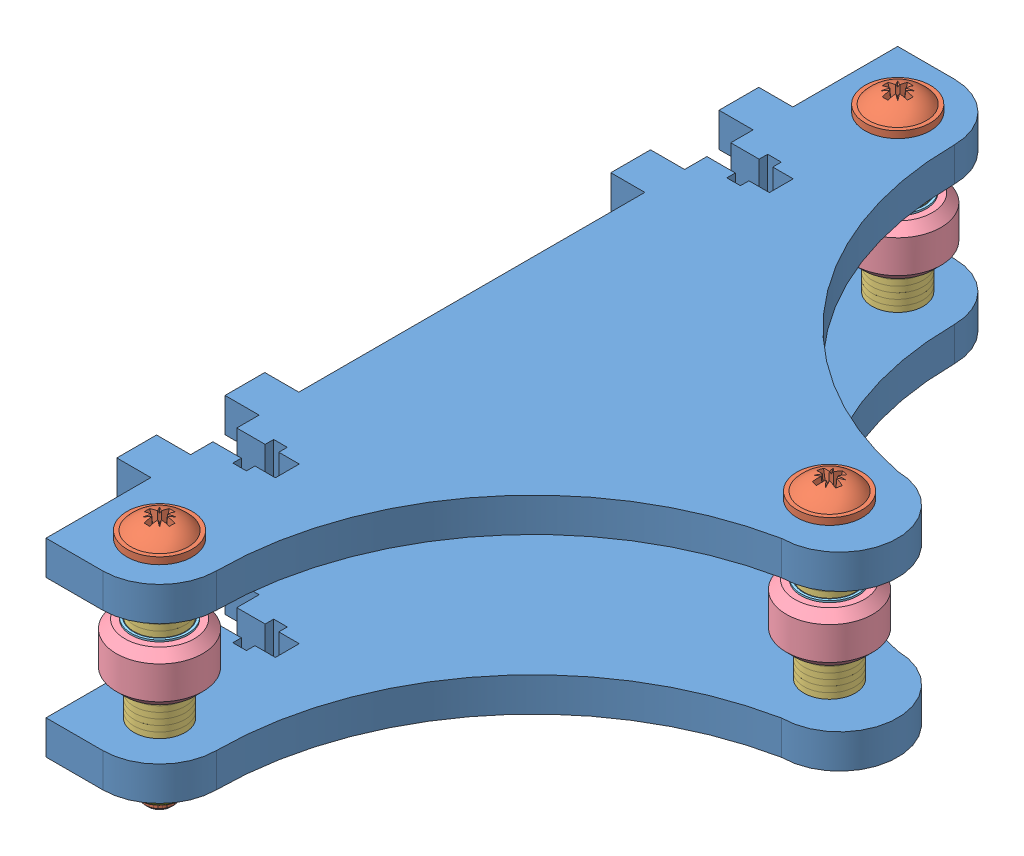
SolidWorks assembly carriage_axis_z, configuration По умолчанию. Lengths in mm.
Overall size (90 43.47 164.42).
59 component instances, 7 part files, 93 mates.
Components (placement in the parent):
- carriage_axis_z_plywood-3: carriage_axis_z_plywood [По умолчанию] at origin size (81.03 6 150)
- DIN967-1: DIN967 [М5х40] at (-25 9.55 -65) x (0 -1 0) z (0 0 1) size (43.47 34 34.42)
- DIN967-2: DIN967 [М5х40] at (-25 9.55 65) x (0 -1 0) z (0 0 1) size (43.47 34 34.42)
- DIN967-4: DIN967 [М5х40] at (28 9.55 0) x (0 -1 0) z (0.973575 0 0.228367) size (43.47 34 34.42)
- din433_m5-1: din433_m5 [По умолчанию] at (28 0 0) x (1 0 0) z (0 -1 0) size (9 9 1)
- din433_m5-2: din433_m5 [По умолчанию] at (28 -2 0) x (-0.882011 0 -0.471229) z (0 1 0) size (9 9 1)
- din433_m5-3: din433_m5 [По умолчанию] at (28 -3 0) x (-0.882011 0 -0.471229) z (0 1 0) size (9 9 1)
- din433_m5-4: din433_m5 [По умолчанию] at (28 -4 0) x (-0.882011 0 -0.471229) z (0 1 0) size (9 9 1)
- din433_m5-5: din433_m5 [По умолчанию] at (28 -5 0) x (-0.986157 0 -0.165812) z (0 1 0) size (9 9 1)
- din433_m5-12: din433_m5 [По умолчанию] at (-25 -3 65) x (-0.955012 0 -0.296566) z (0 1 0) size (9 9 1)
- din433_m5-13: din433_m5 [По умолчанию] at (-25 -4 65) x (-0.955012 0 -0.296566) z (0 1 0) size (9 9 1)
- din433_m5-14: din433_m5 [По умолчанию] at (-25 -5 65) x (-0.827257 0 -0.561823) z (0 1 0) size (9 9 1)
- din433_m5-15: din433_m5 [По умолчанию] at (-25 -2 65) x (-0.955012 0 -0.296566) z (0 1 0) size (9 9 1)
- din433_m5-16: din433_m5 [По умолчанию] at (-25 0 65) x (0.982082 0 -0.188455) z (0 -1 0) size (9 9 1)
- din433_m5-17: din433_m5 [По умолчанию] at (-25 -2 -65) x (-0.996489 0 -0.083718) z (0 1 0) size (9 9 1)
- din433_m5-18: din433_m5 [По умолчанию] at (-25 -3 -65) x (-0.996489 0 -0.083718) z (0 1 0) size (9 9 1)
- din433_m5-19: din433_m5 [По умолчанию] at (-25 -4 -65) x (-0.928921 0 -0.370279) z (0 1 0) size (9 9 1)
- din433_m5-20: din433_m5 [По умолчанию] at (-25 -1 -65) x (-0.996489 0 -0.083718) z (0 1 0) size (9 9 1)
- din433_m5-28: din433_m5 [По умолчанию] at (-25 -5 -65) x (0.980186 0 0.198081) z (0 -1 0) size (9 9 1)
- din433_m5-29: din433_m5 [По умолчанию] at (-25 -4 -65) x (0.980186 0 0.198081) z (0 -1 0) size (9 9 1)
- din433_m5-27: din433_m5 [По умолчанию] at (28 -5 0) x (0.91627 0 0.40056) z (0 -1 0) size (9 9 1)
- din433_m5-21: din433_m5 [По умолчанию] at (-25 -6 65) x (-0.552382 0 -0.833591) z (0 1 0) size (9 9 1)
- Delrin Mini V Wheel Kit-1: Delrin Mini V Wheel Kit [По умолчанию] at (-25 -10.7 65) x (0 1 0) z (0 0 1) size (9.4 15.23 15.23)
  - Delrin Mini V Wheel-1: Delrin Mini V Wheel [Default] at origin size (8.8 15.23 15.23)
  - Mini Ball Bearing 105zz 5x10x4-1: Mini Ball Bearing 105zz 5x10x4 [Default] at (2.6 0 0) size (4.2 10 10)
  - Mini Ball Bearing 105zz 5x10x4-2: Mini Ball Bearing 105zz 5x10x4 [Default] at (-2.6 0 0) size (4.2 10 10)
  - Mini V Wheel Precision Shim-2: Mini V Wheel Precision Shim [По умолчанию] at (-0.5 0 0) size (1 8 8)
- din433_m5-30: din433_m5 [По умолчанию] at (-25 -19.4 65) x (0.999952 0 0.009811) z (0 -1 0) size (9 9 1)
- din433_m5-31: din433_m5 [По умолчанию] at (-25 -20.4 65) x (0.999952 0 0.009811) z (0 -1 0) size (9 9 1)
- din433_m5-32: din433_m5 [По умолчанию] at (-25 -16.4 65) x (-0.994411 0 0.105575) z (0 1 0) size (9 9 1)
- din433_m5-33: din433_m5 [По умолчанию] at (-25 -19.4 65) x (-0.982057 0 -0.188585) z (0 1 0) size (9 9 1)
- din433_m5-34: din433_m5 [По умолчанию] at (-25 -18.4 65) x (-0.994411 0 0.105575) z (0 1 0) size (9 9 1)
- din433_m5-35: din433_m5 [По умолчанию] at (-25 -17.4 65) x (-0.994411 0 0.105575) z (0 1 0) size (9 9 1)
- Delrin Mini V Wheel Kit-2: Delrin Mini V Wheel Kit [По умолчанию] at (-25 -10.7 -65) x (0 -1 0) z (0.990454 0 -0.137844) size (9.4 15.23 15.23)
  - Delrin Mini V Wheel-1: Delrin Mini V Wheel [Default] at origin size (8.8 15.23 15.23)
  - Mini Ball Bearing 105zz 5x10x4-1: Mini Ball Bearing 105zz 5x10x4 [Default] at (2.6 0 0) size (4.2 10 10)
  - Mini Ball Bearing 105zz 5x10x4-2: Mini Ball Bearing 105zz 5x10x4 [Default] at (-2.6 0 0) size (4.2 10 10)
  - Mini V Wheel Precision Shim-2: Mini V Wheel Precision Shim [По умолчанию] at (-0.5 0 0) size (1 8 8)
- din433_m5-42: din433_m5 [По умолчанию] at (-25 -20.4 -65) x (0.983884 0 -0.17881) z (0 -1 0) size (9 9 1)
- din433_m5-43: din433_m5 [По умолчанию] at (-25 -16.4 -65) x (-0.956697 0 0.291085) z (0 1 0) size (9 9 1)
- din433_m5-44: din433_m5 [По умолчанию] at (-25 -19.4 -65) x (-1 0 -0.000132) z (0 1 0) size (9 9 1)
- din433_m5-45: din433_m5 [По умолчанию] at (-25 -18.4 -65) x (-0.956697 0 0.291085) z (0 1 0) size (9 9 1)
- din433_m5-46: din433_m5 [По умолчанию] at (-25 -17.4 -65) x (-0.956697 0 0.291085) z (0 1 0) size (9 9 1)
- din433_m5-47: din433_m5 [По умолчанию] at (-25 -19.4 -65) x (0.983884 0 -0.17881) z (0 -1 0) size (9 9 1)
- Delrin Mini V Wheel Kit-4: Delrin Mini V Wheel Kit [По умолчанию] at (28 -10.7 0) x (0 -1 0) z (-0.546944 0 0.837169) size (9.4 15.23 15.23)
  - Delrin Mini V Wheel-1: Delrin Mini V Wheel [Default] at origin size (8.8 15.23 15.23)
  - Mini Ball Bearing 105zz 5x10x4-1: Mini Ball Bearing 105zz 5x10x4 [Default] at (2.6 0 0) size (4.2 10 10)
  - Mini Ball Bearing 105zz 5x10x4-2: Mini Ball Bearing 105zz 5x10x4 [Default] at (-2.6 0 0) size (4.2 10 10)
  - Mini V Wheel Precision Shim-2: Mini V Wheel Precision Shim [По умолчанию] at (-0.5 0 0) size (1 8 8)
- din433_m5-54: din433_m5 [По умолчанию] at (28 -16.4 0) x (-0.124351 0 0.992238) z (0 1 0) size (9 9 1)
- din433_m5-55: din433_m5 [По умолчанию] at (28 -19.4 0) x (-0.982107 0 0.188325) z (0 1 0) size (9 9 1)
- din433_m5-56: din433_m5 [По умолчанию] at (28 -18.4 0) x (-0.884699 0 0.466164) z (0 1 0) size (9 9 1)
- din433_m5-57: din433_m5 [По умолчанию] at (28 -17.4 0) x (-0.884699 0 0.466164) z (0 1 0) size (9 9 1)
- din433_m5-58: din433_m5 [По умолчанию] at (28 -19.4 0) x (0.932557 0 -0.361024) z (0 -1 0) size (9 9 1)
- din433_m5-59: din433_m5 [По умолчанию] at (28 -20.4 0) x (0.932557 0 -0.361024) z (0 -1 0) size (9 9 1)
- carriage_axis_z_plywood-4: carriage_axis_z_plywood [По умолчанию] at (0 -27.4 0) size (81.03 6 150)
- DIN 985-1: DIN 985 [Verzle DIN 985 - M5] at (-25 -27.4 -65) x (0 1 0) z (1 0 0) size (5 9.24 8)
- DIN 985-2: DIN 985 [Verzle DIN 985 - M5] at (-25 -27.4 65) x (0 1 0) z (1 0 0) size (5 9.24 8)
- DIN 985-4: DIN 985 [Verzle DIN 985 - M5] at (28 -27.4 0) x (0 1 0) z (1 0 0) size (5 9.24 8)
Mates (geometry in assembly coordinates):
- Концентричный11: concentric anti-aligned: cylinder of carriage_axis_z_plywood-3 through (-25 6 -65) axis (0 -1 0) radius 2.55; cylinder of DIN967-1 through (-25 15.9 -65) axis (0 1 0) radius 5.75
- Совпадение11: coincident anti-aligned: plane of carriage_axis_z_plywood-3 through (40.9431 6 -65) normal (0 1 0); plane of DIN967-1 through (-22.5 6 -65) normal (0 -1 0)
- Концентричный21: concentric anti-aligned: cylinder of carriage_axis_z_plywood-3 through (-25 6 65) axis (0 -1 0) radius 2.55; cylinder of DIN967-2 through (-25 15.9 65) axis (0 1 0) radius 5.75
- Совпадение21: coincident anti-aligned: plane of carriage_axis_z_plywood-3 through (40.9431 6 -65) normal (0 1 0); plane of DIN967-2 through (-22.5 6 65) normal (0 -1 0)
- Совпадение41: coincident anti-aligned: plane of carriage_axis_z_plywood-3 through (40.9431 6 -65) normal (0 1 0); plane of DIN967-4 through (28.5709 6 -2.4339) normal (0 -1 0)
- Совпадение5: coincident anti-aligned: plane of carriage_axis_z_plywood-3 through (40.9431 0 -65) normal (0 -1 0); plane of din433_m5-1 through (28 0 0) normal (0 1 0)
- Концентричный6: concentric anti-aligned: cylinder of DIN967-4 through (28 15.9 0) axis (0 1 0) radius 2.5; circle of din433_m5-1
- Концентричный7: concentric aligned: cylinder of DIN967-4 through (28 15.9 0) axis (0 1 0) radius 2.5; circle of din433_m5-2
- Совпадение7: coincident anti-aligned: plane of din433_m5-1 through (28 -1 0) normal (0 -1 0); plane of din433_m5-2 through (28 -1 0) normal (0 1 0)
- Совпадение10: coincident anti-aligned: plane of din433_m5-3 through (28 -3 0) normal (0 -1 0); plane of din433_m5-4 through (28 -3 0) normal (0 1 0)
- Совпадение11: coincident aligned: circle of din433_m5-3; circle of din433_m5-4
- Совпадение12: coincident anti-aligned: plane of din433_m5-4 through (28 -4 0) normal (0 -1 0); plane of din433_m5-5 through (28 -4 0) normal (0 1 0)
- Совпадение13: coincident aligned: circle of din433_m5-4; circle of din433_m5-5
- Совпадение14: coincident anti-aligned: plane of din433_m5-2 through (28 -2 0) normal (0 -1 0); plane of din433_m5-3 through (28 -2 0) normal (0 1 0)
- Совпадение15: coincident aligned: circle of din433_m5-2; circle of din433_m5-3
- Совпадение24: coincident anti-aligned: plane of din433_m5-15 through (-25 -1 65) normal (0 1 0); plane of din433_m5-16 through (-25 -1 65) normal (0 -1 0)
- Совпадение25: coincident anti-aligned: plane of din433_m5-12 through (-25 -3 65) normal (0 -1 0); plane of din433_m5-13 through (-25 -3 65) normal (0 1 0)
- Совпадение26: coincident aligned: circle of din433_m5-12; circle of din433_m5-13
- Совпадение27: coincident anti-aligned: plane of din433_m5-13 through (-25 -4 65) normal (0 -1 0); plane of din433_m5-14 through (-25 -4 65) normal (0 1 0)
- Совпадение28: coincident aligned: circle of din433_m5-13; circle of din433_m5-14
- Совпадение29: coincident anti-aligned: plane of din433_m5-12 through (-25 -2 65) normal (0 1 0); plane of din433_m5-15 through (-25 -2 65) normal (0 -1 0)
- Совпадение30: coincident aligned: circle of din433_m5-12; circle of din433_m5-15
- Совпадение33: coincident anti-aligned: plane of din433_m5-17 through (-25 -2 -65) normal (0 -1 0); plane of din433_m5-18 through (-25 -2 -65) normal (0 1 0)
- Совпадение34: coincident aligned: circle of din433_m5-17; circle of din433_m5-18
- Совпадение35: coincident anti-aligned: plane of din433_m5-18 through (-25 -3 -65) normal (0 -1 0); plane of din433_m5-19 through (-25 -3 -65) normal (0 1 0)
- Совпадение36: coincident aligned: circle of din433_m5-18; circle of din433_m5-19
- Совпадение37: coincident anti-aligned: plane of din433_m5-17 through (-25 -1 -65) normal (0 1 0); plane of din433_m5-20 through (-25 -1 -65) normal (0 -1 0)
- Совпадение38: coincident aligned: circle of din433_m5-17; circle of din433_m5-20
- Концентричный15: concentric aligned: cylinder of DIN967-2 through (-25 15.9 65) axis (0 1 0) radius 2.5; circle of din433_m5-14
- Концентричный16: concentric anti-aligned: cylinder of DIN967-2 through (-25 15.9 65) axis (0 1 0) radius 2.5; circle of din433_m5-16
- Совпадение54: coincident anti-aligned: plane of din433_m5-14 through (-25 -5 65) normal (0 -1 0); plane of din433_m5-21 through (-25 -5 65) normal (0 1 0)
- Концентричный17: concentric aligned: cylinder of DIN967-2 through (-25 15.9 65) axis (0 1 0) radius 2.5; circle of din433_m5-21
- Совпадение55: coincident anti-aligned: plane of din433_m5-5 through (28 -5 0) normal (0 -1 0); plane of din433_m5-27 through (28 -5 0) normal (0 1 0)
- Концентричный18: concentric anti-aligned: cylinder of DIN967-4 through (28 15.9 0) axis (0 1 0) radius 2.5; circle of din433_m5-27
- Концентричный19: concentric aligned: cylinder of DIN967-1 through (-25 15.9 -65) axis (0 1 0) radius 2.5; circle of din433_m5-20
- Совпадение56: coincident anti-aligned: plane of din433_m5-19 through (-25 -4 -65) normal (0 -1 0); plane of din433_m5-29 through (-25 -4 -65) normal (0 1 0)
- Концентричный20: concentric anti-aligned: cylinder of DIN967-1 through (-25 15.9 -65) axis (0 1 0) radius 2.5; circle of din433_m5-29
- Совпадение57: coincident anti-aligned: plane of din433_m5-28 through (-25 -5 -65) normal (0 1 0); plane of din433_m5-29 through (-25 -5 -65) normal (0 -1 0)
- Концентричный21: concentric anti-aligned: cylinder of DIN967-1 through (-25 15.9 -65) axis (0 1 0) radius 2.5; circle of din433_m5-28
- Совпадение58: coincident anti-aligned: plane of carriage_axis_z_plywood-3 through (40.9431 0 -65) normal (0 -1 0); plane of din433_m5-20 through (-25 0 -65) normal (0 1 0)
- Совпадение59: coincident anti-aligned: plane of din433_m5-21 through (-25 -6 65) normal (0 -1 0); plane of Delrin Mini V Wheel Kit-1/Mini Ball Bearing 105zz 5x10x4-1 through (-27.5 -6 65) normal (0 1 0)
- Совпадение60: coincident aligned: cylinder of DIN967-2 through (-25 15.9 65) axis (0 1 0) radius 2.5; circle of Delrin Mini V Wheel Kit-1/Mini Ball Bearing 105zz 5x10x4-2
- Совпадение61: coincident anti-aligned: plane of din433_m5-34 through (-25 -17.4 65) normal (0 1 0); plane of din433_m5-35 through (-25 -17.4 65) normal (0 -1 0)
- Совпадение62: coincident aligned: circle of din433_m5-34; circle of din433_m5-35
- Совпадение63: coincident anti-aligned: plane of din433_m5-33 through (-25 -18.4 65) normal (0 1 0); plane of din433_m5-34 through (-25 -18.4 65) normal (0 -1 0)
- Совпадение64: coincident aligned: circle of din433_m5-33; circle of din433_m5-34
- Совпадение65: coincident anti-aligned: plane of din433_m5-32 through (-25 -16.4 65) normal (0 -1 0); plane of din433_m5-35 through (-25 -16.4 65) normal (0 1 0)
- Совпадение67: coincident anti-aligned: plane of din433_m5-30 through (-25 -19.4 65) normal (0 1 0); plane of din433_m5-33 through (-25 -19.4 65) normal (0 -1 0)
- Совпадение68: coincident anti-aligned: plane of din433_m5-30 through (-25 -20.4 65) normal (0 -1 0); plane of din433_m5-31 through (-25 -20.4 65) normal (0 1 0)
- Совпадение80: coincident anti-aligned: plane of Delrin Mini V Wheel Kit-1/Mini Ball Bearing 105zz 5x10x4-2 through (-27.5 -15.4 65) normal (0 -1 0); plane of din433_m5-32 through (-25 -15.4 65) normal (0 1 0)
- Концентричный22: concentric aligned: cylinder of DIN967-2 through (-25 15.9 65) axis (0 1 0) radius 2.5; circle of din433_m5-32
- Концентричный23: concentric aligned: cylinder of DIN967-2 through (-25 15.9 65) axis (0 1 0) radius 2.5; circle of din433_m5-35
- Концентричный24: concentric anti-aligned: cylinder of DIN967-2 through (-25 15.9 65) axis (0 1 0) radius 2.5; circle of din433_m5-30
- Концентричный25: concentric aligned: cylinder of DIN967-2 through (-25 15.9 65) axis (0 1 0) radius 2.5; cylinder of din433_m5-31 through (-25 -21.4 65) axis (0 1 0) radius 4.5
- Совпадение81: coincident anti-aligned: plane of din433_m5-28 through (-25 -6 -65) normal (0 -1 0); plane of Delrin Mini V Wheel Kit-2/Mini Ball Bearing 105zz 5x10x4-2 through (-25.3446 -6 -67.4761) normal (0 1 0)
- Совпадение82: coincident anti-aligned: cylinder of DIN967-1 through (-25 15.9 -65) axis (0 1 0) radius 2.5; circle of Delrin Mini V Wheel Kit-2/Mini Ball Bearing 105zz 5x10x4-1
- Совпадение83: coincident anti-aligned: plane of din433_m5-45 through (-25 -17.4 -65) normal (0 1 0); plane of din433_m5-46 through (-25 -17.4 -65) normal (0 -1 0)
- Совпадение84: coincident aligned: circle of din433_m5-45; circle of din433_m5-46
- Совпадение85: coincident anti-aligned: plane of din433_m5-44 through (-25 -18.4 -65) normal (0 1 0); plane of din433_m5-45 through (-25 -18.4 -65) normal (0 -1 0)
- Совпадение86: coincident aligned: circle of din433_m5-44; circle of din433_m5-45
- Совпадение87: coincident anti-aligned: plane of din433_m5-43 through (-25 -16.4 -65) normal (0 -1 0); plane of din433_m5-46 through (-25 -16.4 -65) normal (0 1 0)
- Совпадение88: coincident anti-aligned: plane of din433_m5-44 through (-25 -19.4 -65) normal (0 -1 0); plane of din433_m5-47 through (-25 -19.4 -65) normal (0 1 0)
- Совпадение89: coincident anti-aligned: plane of din433_m5-42 through (-25 -20.4 -65) normal (0 1 0); plane of din433_m5-47 through (-25 -20.4 -65) normal (0 -1 0)
- Совпадение99: coincident anti-aligned: plane of carriage_axis_z_plywood-3 through (40.9431 0 -65) normal (0 -1 0); plane of din433_m5-16 through (-25 0 65) normal (0 1 0)
- Совпадение100: coincident anti-aligned: plane of Delrin Mini V Wheel Kit-2/Mini Ball Bearing 105zz 5x10x4-1 through (-25.3446 -15.4 -67.4761) normal (0 -1 0); plane of din433_m5-43 through (-25 -15.4 -65) normal (0 1 0)
- Концентричный26: concentric anti-aligned: circle of din433_m5-42; circle of din433_m5-43
- Концентричный27: concentric anti-aligned: circle of din433_m5-43; circle of din433_m5-47
- Концентричный28: concentric anti-aligned: circle of din433_m5-42; circle of din433_m5-44
- Концентричный29: concentric aligned: circle of Delrin Mini V Wheel Kit-2/Mini Ball Bearing 105zz 5x10x4-1; cylinder of din433_m5-43 through (-25 -15.4 -65) axis (0 -1 0) radius 4.5
- Совпадение106: coincident anti-aligned: plane of din433_m5-27 through (28 -6 0) normal (0 -1 0); plane of Delrin Mini V Wheel Kit-4/Mini Ball Bearing 105zz 5x10x4-2 through (30.0929 -6 1.3674) normal (0 1 0)
- Концентричный30: concentric anti-aligned: cylinder of DIN967-4 through (28 15.9 0) axis (0 1 0) radius 2.5; cylinder of Delrin Mini V Wheel Kit-4/Mini Ball Bearing 105zz 5x10x4-1 through (28 -13.3 0) axis (0 -1 0) radius 2.5
- Совпадение107: coincident anti-aligned: plane of din433_m5-56 through (28 -17.4 0) normal (0 1 0); plane of din433_m5-57 through (28 -17.4 0) normal (0 -1 0)
- Совпадение108: coincident aligned: circle of din433_m5-56; circle of din433_m5-57
- Совпадение109: coincident anti-aligned: plane of din433_m5-55 through (28 -18.4 0) normal (0 1 0); plane of din433_m5-56 through (28 -18.4 0) normal (0 -1 0)
- Совпадение110: coincident aligned: circle of din433_m5-55; circle of din433_m5-56
- Совпадение111: coincident anti-aligned: plane of din433_m5-54 through (28 -16.4 0) normal (0 -1 0); plane of din433_m5-57 through (28 -16.4 0) normal (0 1 0)
- Совпадение112: coincident anti-aligned: plane of din433_m5-55 through (28 -19.4 0) normal (0 -1 0); plane of din433_m5-58 through (28 -19.4 0) normal (0 1 0)
- Совпадение113: coincident anti-aligned: plane of din433_m5-58 through (28 -20.4 0) normal (0 -1 0); plane of din433_m5-59 through (28 -20.4 0) normal (0 1 0)
- Концентричный31: concentric anti-aligned: circle of din433_m5-54; circle of din433_m5-59
- Концентричный32: concentric anti-aligned: circle of din433_m5-54; circle of din433_m5-58
- Концентричный33: concentric anti-aligned: circle of din433_m5-55; circle of din433_m5-59
- Совпадение208: coincident anti-aligned: plane of Delrin Mini V Wheel Kit-4/Mini Ball Bearing 105zz 5x10x4-1 through (30.0929 -15.4 1.3674) normal (0 -1 0); plane of din433_m5-54 through (28 -15.4 0) normal (0 1 0)
- Концентричный87: concentric aligned: cylinder of DIN967-4 through (28 15.9 0) axis (0 1 0) radius 2.5; circle of din433_m5-54
- Концентричный88: concentric anti-aligned: cylinder of DIN967-1 through (-25 15.9 -65) axis (0 1 0) radius 2.5; circle of carriage_axis_y_plywood_left-2
- Концентричный89: concentric anti-aligned: cylinder of DIN967-2 through (-25 15.9 65) axis (0 1 0) radius 2.5; circle of carriage_axis_y_plywood_left-2
- Совпадение210: coincident anti-aligned: plane of din433_m5-42 through (-25 -21.4 -65) normal (0 -1 0); plane of carriage_axis_z_plywood-4 through (40.9431 -21.4 -65) normal (0 1 0)
- Совпадение211: coincident anti-aligned: plane of carriage_axis_z_plywood-4 through (40.9431 -27.4 -65) normal (0 -1 0); plane of DIN 985-1 through (-25 -27.4 -65) normal (0 1 0)
- Концентричный90: concentric anti-aligned: cylinder of DIN967-1 through (-25 15.9 -65) axis (0 1 0) radius 2.5; cylinder of DIN 985-1 through (-25 -35.522 -65) axis (0 -1 0) radius 2.5
- Совпадение212: coincident anti-aligned: plane of carriage_axis_z_plywood-4 through (40.9431 -27.4 -65) normal (0 -1 0); plane of DIN 985-2 through (-25 -27.4 65) normal (0 1 0)
- Совпадение213: coincident anti-aligned: plane of carriage_axis_z_plywood-4 through (40.9431 -27.4 -65) normal (0 -1 0); plane of DIN 985-4 through (28 -27.4 0) normal (0 1 0)
- Концентричный91: concentric anti-aligned: cylinder of DIN967-2 through (-25 15.9 65) axis (0 1 0) radius 2.5; cylinder of DIN 985-2 through (-25 -35.522 65) axis (0 -1 0) radius 2.5
- Концентричный93: concentric anti-aligned: cylinder of DIN967-4 through (28 15.9 0) axis (0 1 0) radius 2.5; cylinder of DIN 985-4 through (28 -35.522 0) axis (0 -1 0) radius 2.5
- Концентричный94: concentric anti-aligned: circle of carriage_axis_z_plywood-3; cylinder of DIN967-4 through (28 15.9 0) axis (0 1 0) radius 2.5
